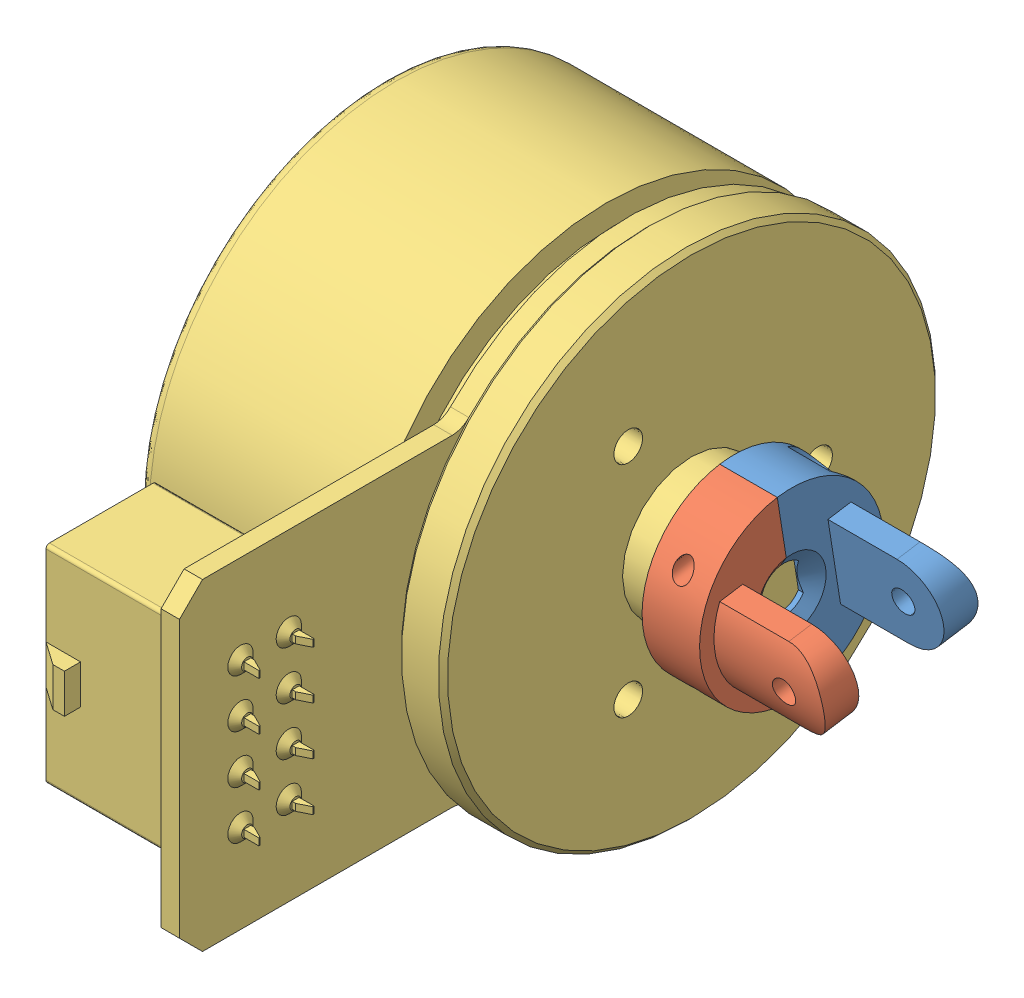
SolidWorks assembly Rear_Right Drivetrain Block, configuration Default. Lengths in mm.
8 component instances, 7 part files, 14 mates.
Components (placement in the parent):
- Rear drivemount_proto-1: Rear drivemount_proto [Default] at (-50.5218 14.7982 15.1074) (suppressed, hidden)
- Shaftcoupler-1: Shaftcoupler [Default] at (-19.701 9.806 23.7153) x (0 0.987792 0.155779) z (0 0.155779 -0.987792) size (16 14.5 16)
  - Shaft Coupler - SideA-1: Shaft Coupler - SideA [Default] at (3.5903 3.9792 9.2805) size (16 14.5 8)
  - Shaft Coupler - SideB-1: Shaft Coupler - SideB [Default] at (3.5903 3.9792 9.2805) x (-1 0 0) z (0 0 -1) size (16 14.5 8)
- MaxonMotor-1: MaxonMotor [Default] at (-21.9218 14.7982 15.1074) x (-1 0 0) z (0 -1 0) size (34.5 62.1 43.2)
- Rear A Pivot_L-1: Rear A Pivot_L [Default] at (-11.7218 -2.2018 12.1074) x (0 0 1) z (-1 0 0) (suppressed, hidden)
- Rear Turnbucklemount_L-1: Rear Turnbucklemount_L [Default] at (-16.7218 28.7982 4.1074) x (0 0 1) z (-1 0 0) (suppressed, hidden)
- Rear upright_l-1: Rear upright_l [Default] at (-38.7218 41.681 27.1074) x (0 0 -1) z (1 0 0) (suppressed, hidden)
Mates (geometry in assembly coordinates):
- Concentric1: concentric anti-aligned: cylinder of Rear drivemount_proto-1 through (-50.5218 14.7982 15.1074) axis (1 0 0) radius 6.5; cylinder of Shaftcoupler-1/Shaft Coupler - SideB-1 through (-13.2218 14.7982 15.1074) axis (-1 0 0) radius 2
- Distance1: distance = 0.5 mm anti-aligned: plane of Shaftcoupler-1/Shaft Coupler - SideB-1 through (-18.2218 14.7982 15.1074) normal (-1 0 0); plane of Rear drivemount_proto-1 through (-18.7218 14.7982 15.1074) normal (1 0 0)
- Concentric2: concentric anti-aligned: cylinder of Rear drivemount_proto-1 through (-50.5218 14.7982 15.1074) axis (1 0 0) radius 6.5; cylinder of MaxonMotor-1 through (-21.9218 14.7982 15.1074) axis (-1 0 0) radius 6
- Concentric4: concentric aligned: cylinder of Rear drivemount_proto-1 through (-18.7218 14.7982 4.1074) axis (1 0 0) radius 1.7; cylinder of MaxonMotor-1 through (-21.9218 14.7982 4.1074) axis (1 0 0) radius 1.25
- Coincident2: coincident anti-aligned: plane of Rear drivemount_proto-1 through (-21.9218 14.7982 15.1074) normal (-1 0 0); plane of MaxonMotor-1 through (-21.9218 14.7982 15.1074) normal (1 0 0)
- Concentric5: concentric aligned: cylinder of Rear drivemount_proto-1 through (-18.7218 -10.2018 2.1074) axis (1 0 0) radius 1.25; circle of Rear A Pivot_L-1
- Concentric6: concentric aligned: cylinder of Rear drivemount_proto-1 through (-18.7218 -10.2018 22.1074) axis (1 0 0) radius 1.25; circle of Rear A Pivot_L-1
- Coincident3: coincident anti-aligned: plane of Rear drivemount_proto-1 through (-18.7218 14.7982 15.1074) normal (1 0 0); plane of Rear A Pivot_L-1 through (-18.7218 -14.2018 27.1074) normal (-1 0 0)
- Concentric7: concentric anti-aligned: cylinder of Rear drivemount_proto-1 through (-18.7218 32.7982 8.1074) axis (1 0 0) radius 1.25; circle of Rear Turnbucklemount_L-1
- Concentric8: concentric aligned: cylinder of Rear drivemount_proto-1 through (-18.7218 32.7982 25.1074) axis (1 0 0) radius 1.25; cylinder of Rear Turnbucklemount_L-1 through (-16.7218 32.7982 25.1074) axis (1 0 0) radius 1.7
- Coincident4: coincident anti-aligned: plane of Rear drivemount_proto-1 through (-18.7218 14.7982 15.1074) normal (1 0 0); plane of Rear Turnbucklemount_L-1 through (-18.7218 36.7982 29.1074) normal (-1 0 0)
- Concentric9: concentric aligned: cylinder of Rear drivemount_proto-1 through (-25.7218 40.7982 27.1074) axis (0 1 0) radius 1.25; cylinder of Rear upright_l-1 through (-25.7218 44.7982 27.1074) axis (0 1 0) radius 1.7
- Coincident5: coincident anti-aligned: plane of Rear drivemount_proto-1 through (53.6808 40.7982 31.1074) normal (0 1 0); plane of Rear upright_l-1 through (-38.7218 40.7982 23.1074) normal (0 -1 0)
- Parallel2: parallel aligned: plane of Rear drivemount_proto-1 through (53.6808 -7.2018 31.1074) normal (0 0 1); plane of Rear upright_l-1 through (-38.7218 41.681 31.1074) normal (0 0 1)
